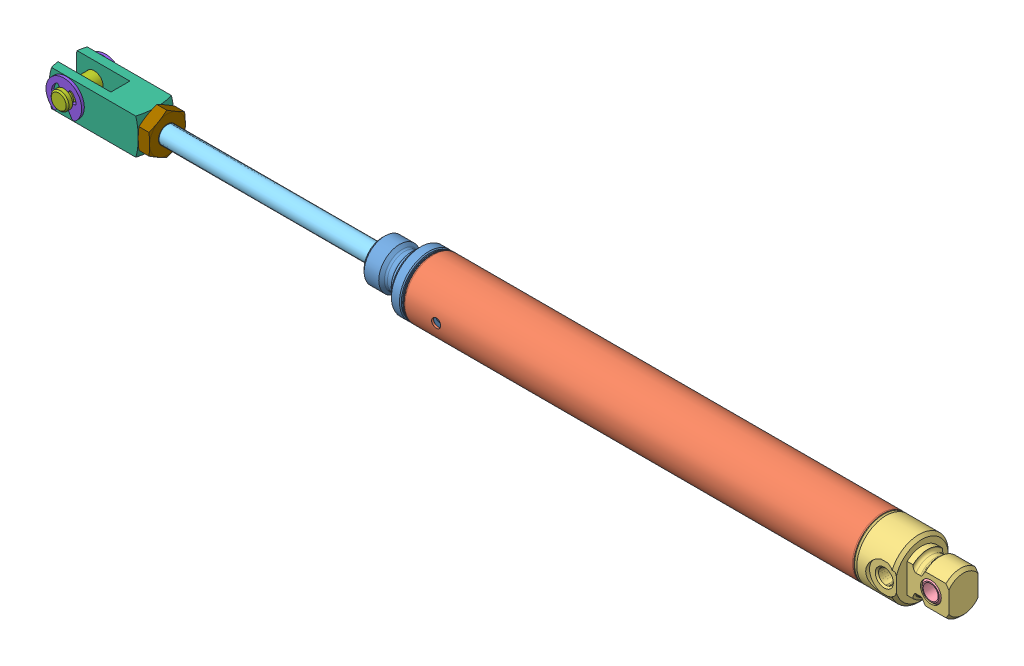
SolidWorks assembly 022_25-P, configuration Default. Lengths in mm.
Overall size (240.09 15.62 15.62).
12 component instances, 10 part files, 17 mates.
Components (placement in the parent):
- 022_25-P0000_0_dummy-1: 022_25-P0000_0_dummy [Default] at origin
- 02000-0_rod_guide-1: 02000-0_rod_guide [Default] at origin size (26.19 15.62 15.62)
- 02-4_7462-1: 02-4_7462 [Default] at (13.335 0 0) size (121.66 15.62 15.62)
- 02P0Y000_rear_head-1: 02P0Y000_rear_head [Default] at (130.5306 0 0) size (24.61 15.62 15.62)
- D-8597-1: D-8597 [Default] at (150.368 0 0) x (1 0 0) z (0 0 -1) size (5.55 5.55 7.92)
- 022_25-P0_rod-1: 022_25-P0_rod [Default] at (-57.15 0 0) size (143.23 14.44 14.44)
- Bimba D-850-1: Bimba D-850 [Default] at (-79.375 0 0) size (27.67 11 13.87)
  - _D-14043-1: _D-14043 [Default] x (1 0 0) z (0 0 -1) size (25.45 9.53 9.53)
  - _D-12304-1: _D-12304 [Default] x (0 0 1) z (-1 0 0) size (13.87 4.75 4.75)
  - _D-5406-1: _D-5406 [Default] at (0 0 5.2134) x (-1 0 0) z (0 0 -1) size (9.53 8.6 0.7)
  - _D-5406-2: _D-5406 [Default] at (0 0 -5.2134) x (-1 0 0) z (0 0 -1) size (9.53 8.6 0.7)
  - _D-5288-1: _D-5288 [Default] at (19.05 0 0) x (0 0 1) z (-1 0 0) size (9.53 11 3.05)
Mates (geometry in assembly coordinates):
- Distance2: distance = 0 mm aligned: plane of 02000-0_rod_guide-1 through (0 0 0) normal (1 0 0); plane of 022_25-P0000_0_dummy-1 through (0 0 0) normal (1 0 0)
- Coincident1: coincident aligned: line of 022_25-P0000_0_dummy-1 through (80.9 0 0) axis (-1 0 0); line of 02000-0_rod_guide-1 through (80.9 0 0) axis (-1 0 0)
- Angle3: planar angle = 0 rad aligned: plane of 02000-0_rod_guide-1 through (0 0 0) normal (0 0 -1); plane of 022_25-P0000_0_dummy-1 through (0 0 0) normal (0 0 -1)
- Distance4: distance = 0 mm aligned: plane of 02-4_7462-1 through (13.335 0 0) normal (1 0 0); plane of 02000-0_rod_guide-1 through (13.335 0 0) normal (1 0 0)
- Coincident2: coincident aligned: line of 02000-0_rod_guide-1 through (80.9 0 0) axis (-1 0 0); line of 02-4_7462-1 through (94.235 0 0) axis (-1 0 0)
- Angle6: planar angle = 0 rad aligned: plane of 02-4_7462-1 through (13.335 0 0) normal (0 0 -1); plane of 02000-0_rod_guide-1 through (0 0 0) normal (0 0 -1)
- Distance6: distance = 0 mm aligned: plane of 02P0Y000_rear_head-1 through (133.8834 0 0) normal (1 0 0); plane of 02-4_7462-1 through (133.8834 0 0) normal (1 0 0)
- Coincident3: coincident aligned: line of 02-4_7462-1 through (94.235 0 0) axis (-1 0 0); line of 02P0Y000_rear_head-1 through (211.4306 0 0) axis (-1 0 0)
- Angle9: planar angle = 0 rad aligned: plane of 02P0Y000_rear_head-1 through (130.5306 0 0) normal (0 0 -1); plane of 02-4_7462-1 through (13.335 0 0) normal (0 0 -1)
- Distance7: distance = 0 mm anti-aligned: plane of D-8597-1 through (150.368 0 0) normal (0 0 -1); plane of 02P0Y000_rear_head-1 through (130.5306 0 0) normal (0 0 1)
- Coincident4: coincident anti-aligned: line of 02P0Y000_rear_head-1 through (150.368 0 80.9) axis (0 0 -1); line of D-8597-1 through (150.368 0 -80.9) axis (0 0 1)
- Angle12: planar angle = 0 rad aligned: plane of D-8597-1; plane of 02P0Y000_rear_head-1 through (150.368 0 0) normal (1 0 0)
- LimitDistance2: limit distance = 57.15 mm aligned: plane of 022_25-P0_rod-1 through (-57.15 0 0) normal (1 0 0); plane of 02000-0_rod_guide-1 through (0 0 0) normal (1 0 0)
- Coincident5: coincident aligned: line of 02000-0_rod_guide-1 through (80.9 0 0) axis (-1 0 0); line of 022_25-P0_rod-1 through (23.75 0 0) axis (-1 0 0)
- Parallel2: parallel aligned: plane of 02P0Y000_rear_head-1 through (144.0434 15.621 3.8989) normal (0 0 1); plane of Bimba D-850-1/_D-14043-1 through (-79.375 0 4.7625) normal (0 0 1)
- Concentric5: concentric aligned: cylinder of 022_25-P0_rod-1 through (-57.15 0 0) axis (-1 0 0) radius 2.413; cylinder of Bimba D-850-1/_D-14043-1 through (-60.325 0 0) axis (-1 0 0) radius 1.9837
- Coincident7: coincident aligned: plane of 022_25-P0_rod-1 through (-69.85 0 0) normal (-1 0 0); plane of Bimba D-850-1/_D-14043-1 through (-69.85 -4.7625 -2.54) normal (-1 0 0)
